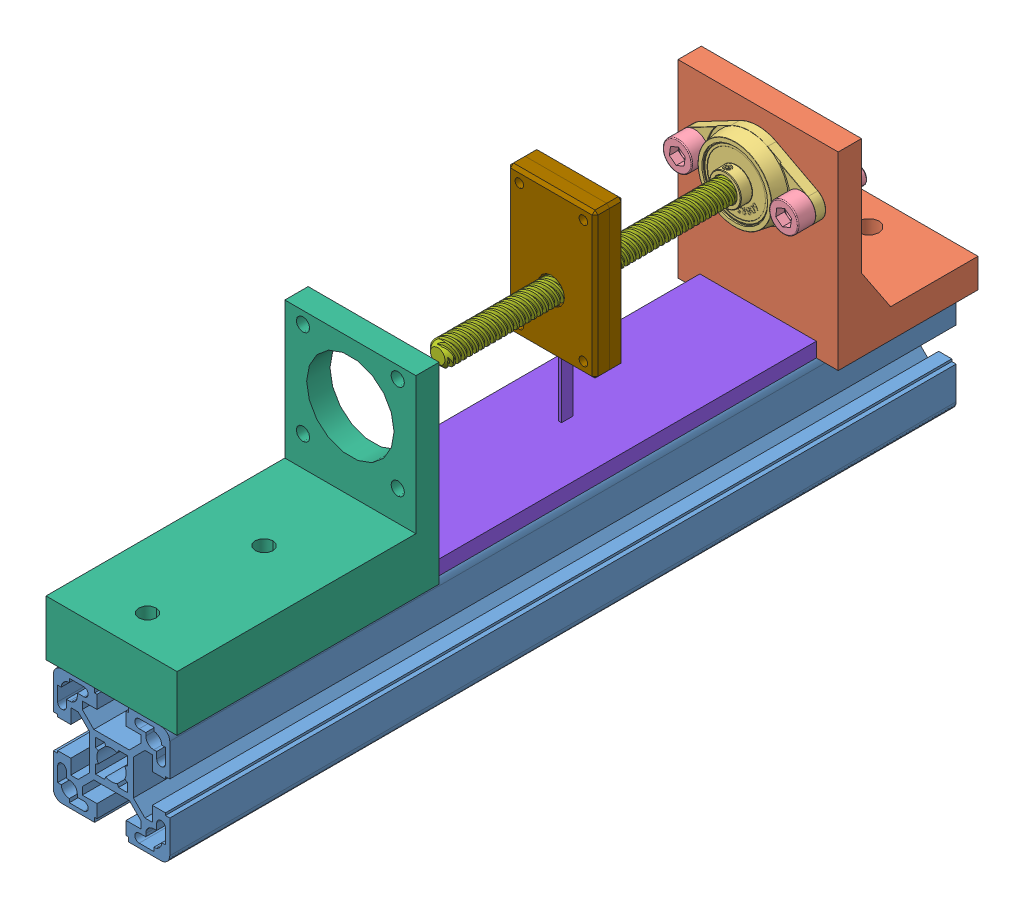
SolidWorks assembly MotorUnit, configuration Default. Lengths in mm.
Overall size (55 116 270).
13 component instances, 9 part files, 17 mates.
Components (placement in the parent):
- Profil250-1: Profil250 [Default] at (118.4285 129.5983 54.234) size (40 40 270)
- MotorMountBearing-1: MotorMountBearing [Default] at (149.8022 130.5737 41.5407) x (0 0 1) z (-1 0 0) size (59.35 65 55)
  - BearingMount-2: BearingMount [Default] at (36.6933 19.0245 31.3737) size (48 65 55)
  - KFL08 -1: KFL08  [Default] at (66.7558 66.0878 -15.1263) x (0 -1 0) z (0 0 1) size (28.12 11.35 47.88)
  - socket head cap screw_bsi-1: socket head cap screw_bsi [BS EN ISO 4762 M6 x 20 - 20N] at (70.1933 64.6245 13.1237) x (-1 0 0) z (0 -0.924225 -0.381849) size (26 10 10)
  - socket head cap screw_bsi-2: socket head cap screw_bsi [BS EN ISO 4762 M6 x 20 - 20N] at (70.1933 64.6245 49.6237) x (-1 0 0) z (0 0.924225 0.381849) size (26 10 10)
  - hex flange nut gradea_bsi-1: hex flange nut gradea_bsi [BS EN ISO - 4161 - M5 - N] at (47.6933 64.6245 13.1237) x (0 0 1) z (-1 0 0) size (11.8 11.8 5)
  - hex flange nut gradea_bsi-2: hex flange nut gradea_bsi [BS EN ISO - 4161 - M5 - N] at (47.6933 64.6245 49.6237) x (0 0 1) z (-1 0 0) size (11.8 11.8 5)
- MotorMount-1: MotorMount [Default] at (118.4285 149.5983 279.234) x (0 0 1) z (-1 0 0) size (90 66 45)
- Trapezoidal lead screw tr8x8-4-1: Trapezoidal lead screw tr8x8-4 [Default] at (118.4285 195.1983 102.234) x (-0.923728 -0.383049 0) z (0 0 -1) size (8.34 8.34 111.99)
- Sensor-1: Sensor [Default] at (118.4285 149.5983 168.234) x (0 0 1) z (-1 0 0) size (132 30 40)
- Runner-1: Runner [Default] at (118.4285 200.5983 173.234) x (0 -1 0) z (1 0 0) size (50 5 30)
- Runner-2: Runner [Default] at (118.4285 200.5983 163.234) x (0 -1 0) z (-1 0 0) size (50 5 30)
Mates (geometry in assembly coordinates):
- Coincident1: coincident anti-aligned: plane of MotorMountBearing-1/BearingMount-2 through (118.4285 149.5983 78.234) normal (-1 0 0); plane of assembly through (118.4285 0 0) normal (1 0 0)
- Coincident2: coincident anti-aligned: plane of Profil250-1 through (124.2285 149.5983 324.234) normal (0 1 0); plane of MotorMountBearing-1/BearingMount-2 through (118.4285 149.5983 78.234) normal (0 -1 0)
- Coincident3: coincident aligned: plane of Profil250-1 through (135.4285 112.5983 54.234) normal (0 0 -1); plane of MotorMountBearing-1/BearingMount-2 through (145.9285 159.5983 54.234) normal (0 0 -1)
- Coincident4: coincident anti-aligned: plane of Profil250-1 through (124.2285 149.5983 324.234) normal (0 1 0); plane of MotorMount-1 through (118.4285 149.5983 279.234) normal (0 -1 0)
- Coincident5: coincident anti-aligned: plane of MotorMount-1 through (118.4285 149.5983 279.234) normal (-1 0 0); plane of assembly through (118.4285 0 0) normal (1 0 0)
- Coincident6: coincident aligned: plane of Profil250-1 through (135.4285 112.5983 324.234) normal (0 0 1); plane of MotorMount-1 through (140.9285 154.5983 324.234) normal (0 0 1)
- Coincident7: coincident anti-aligned: line of MotorMountBearing-1/KFL08 -1 through (118.4285 195.1983 113.384) axis (0 0 1); line of Trapezoidal lead screw tr8x8-4-1 through (118.4285 195.1983 210.734) axis (0 0 -1)
- Coincident8: coincident anti-aligned: plane of MotorMountBearing-1/BearingMount-2 through (145.9285 159.5983 102.234) normal (0 0 1); plane of Trapezoidal lead screw tr8x8-4-1 through (118.4285 195.1983 102.234) normal (0 0 -1)
- Coincident10: coincident anti-aligned: plane of Profil250-1 through (112.6285 149.5983 324.234) normal (0 1 0); plane of Sensor-1 through (118.4285 149.5983 168.234) normal (0 -1 0)
- Coincident11: coincident aligned: plane of Profil250-1 through (98.4285 146.5983 324.234) normal (-1 0 0); plane of Sensor-1 through (98.4285 154.5983 102.234) normal (-1 0 0)
- Distance2: distance = 0 mm anti-aligned: plane of MotorMount-1 through (140.9285 154.5983 234.234) normal (0 0 -1); plane of Sensor-1 through (138.4285 154.5983 234.234) normal (0 0 1)
- Coincident15: coincident aligned: line of Trapezoidal lead screw tr8x8-4-1 through (118.4285 195.1983 210.734) axis (0 0 -1); line of Runner-1 through (118.4285 195.1983 173.234) axis (0 0 -1)
- Parallel2: parallel anti-aligned: plane of Sensor-1 through (118.4285 154.5983 168.234) normal (0 1 0); plane of Runner-1 through (103.4285 175.5983 168.234) normal (0 -1 0)
- Coincident17: coincident anti-aligned: plane of Sensor-1 through (118.9285 179.5983 170.234) normal (0 0 1); plane of Runner-1 through (118.4285 200.5983 170.234) normal (0 0 -1)
- Coincident18: coincident anti-aligned: line of Trapezoidal lead screw tr8x8-4-1 through (118.4285 195.1983 210.734) axis (0 0 -1); line of Runner-2 through (118.4285 195.1983 163.234) axis (0 0 1)
- Coincident19: coincident anti-aligned: plane of Sensor-1 through (118.9285 179.5983 166.234) normal (0 0 -1); plane of Runner-2 through (118.4285 200.5983 166.234) normal (0 0 1)
- Coincident20: coincident anti-aligned: plane of Sensor-1 through (118.9285 179.5983 166.234) normal (0 1 0); plane of Runner-2 through (118.9285 179.5983 166.234) normal (0 -1 0)
